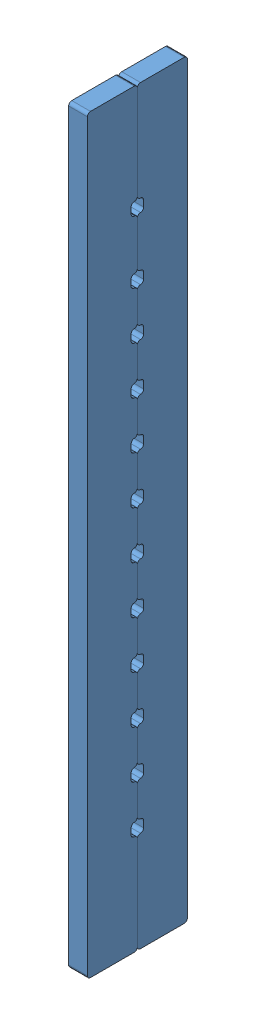
SolidWorks assembly Assem1, configuration Default. Lengths in mm.
Overall size (9.52 381 50.8).
2 component instances, 1 part files, 3 mates.
Components (placement in the parent):
- dreidel holder-1: dreidel holder [Default] at (-49.2319 26.1282 12.3797) size (9.53 381 25.4)
- dreidel holder-2: dreidel holder [Default] at (-39.7069 26.1282 -13.0203) x (-1 0 0) z (0 0 -1) size (9.53 381 25.4)
Mates (geometry in assembly coordinates):
- Coincident1: coincident: plane of dreidel holder-1 through (-39.7069 26.1282 12.3797) normal (1 0 0); plane of dreidel holder-2 through (-39.7069 47.0951 -13.0203) normal (1 0 0)
- Coincident4: coincident: plane of dreidel holder-1 through (-39.7069 26.1282 -0.3203) normal (0 0 -1); plane of dreidel holder-2 through (-49.2319 47.0951 -0.3203) normal (0 0 1)
- Coincident5: coincident aligned: plane of dreidel holder-1 through (-39.7069 -164.3718 12.3797) normal (0 -1 0); plane of dreidel holder-2 through (-49.2319 -164.3718 -13.0203) normal (0 -1 0)
